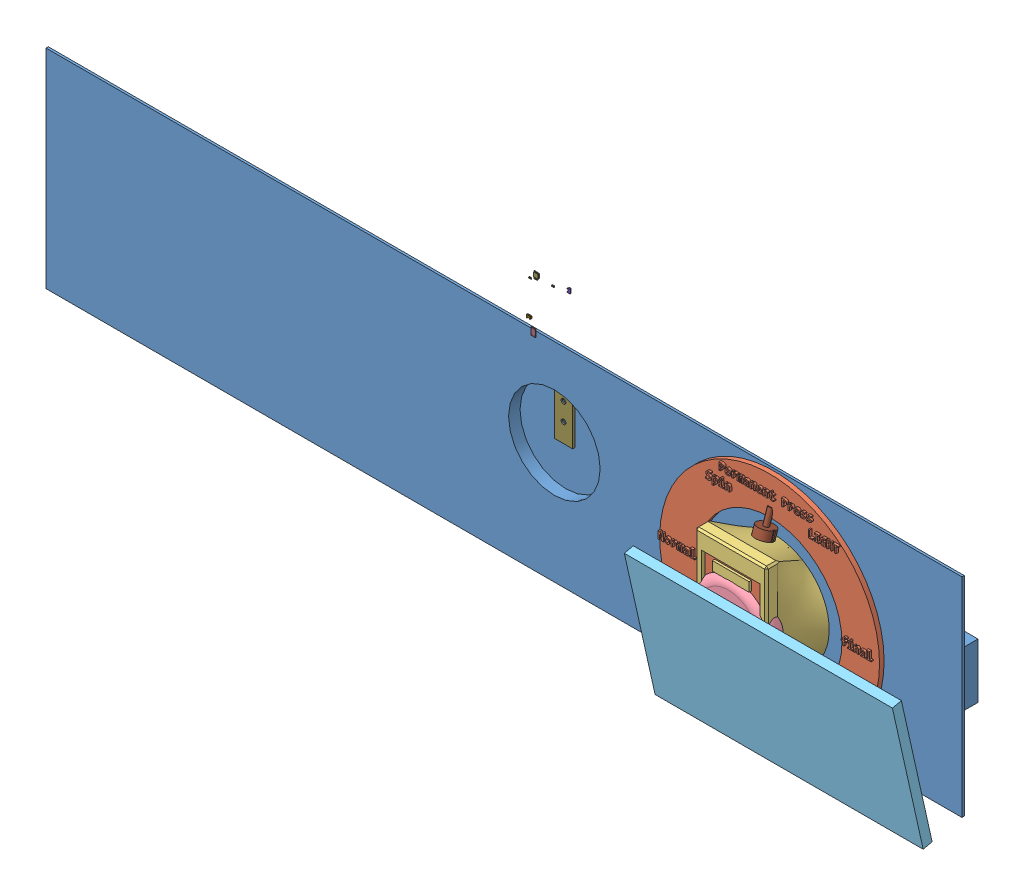
SolidWorks assembly Front Panel, configuration Default. Lengths in mm.
Overall size (635 144.46 57.15).
214 component instances, 49 part files, 26 mates.
Components (placement in the parent):
- MaytagFrontPanel-1: MaytagFrontPanel [Default] at origin size (635 144.46 26.99)
- gen4-uLCD-24PT_simplestepmodel_R_1_0-1: gen4-uLCD-24PT_simplestepmodel_R_1_0 [Default] at (28.5749 -40.2673 92.0062) x (-1 0 0) z (0 0 -1) size (171.91 172.67 8.27) (hidden)
  - gen4-uLCD-24PT_simplestepmodel_R_1_0.STEP-1: gen4-uLCD-24PT_simplestepmodel_R_1_0.STEP [Default] at origin size (171.91 172.67 8.27)
    - Assembly-24PT-NoPCB.STEP-1: Assembly-24PT-NoPCB.STEP [Default] at (-2.1876 3.7664 -0.6753) size (44.92 78.36 8.27)
      - 4DLCD-24T-QVGA-LCD.STEP-1: 4DLCD-24T-QVGA-LCD.STEP [Default] at (30.7625 31.8275 58.2815) x (0 1 0) z (0 0 -1) size (60.86 43.86 8.27)
        - 4DLCD-24T-QVGA-GLASS.STEP-1: 4DLCD-24T-QVGA-GLASS.STEP [Default] at (-0.3756 -1.6155 2.7) size (60.26 42.72 1)
        - 4DLCD-24T-QVGA-METAL.STEP-1: 4DLCD-24T-QVGA-METAL.STEP [Default] at (9.2934 0 0) size (60.26 42.72 2.7)
        - 4DLCD-24T-QVGA-LCDGLASS.STEP-1: 4DLCD-24T-QVGA-LCDGLASS.STEP [Default] at (11.9434 0 2.6) size (48.96 36.72 0.1)
        - 4DLCD-24T-QVGA-FLEX.STEP-1: 4DLCD-24T-QVGA-FLEX.STEP [Default] at (-20.8366 -9.4418 -0.1) x (0 -1 0) z (-1 0 0) size (42.86 5.67 25.87)
        - 4DLCD-24T-QVGA-BASE.STEP-1: 4DLCD-24T-QVGA-BASE.STEP [Default] at (9.2934 0 0) size (58.26 40.72 2.7)
      - gen4-24-PT.STEP-1: gen4-24-PT.STEP [Default] at (24.6025 49.8444 58.3015) size (44.83 78.36 5.75)
    - Assembly-PCB-Picaso-REV1.2.STEP-1: Assembly-PCB-Picaso-REV1.2.STEP [Default] at (11.1775 28.3756 26.4775) size (165.23 149.3 2.88)
      - Gen4-PT-REV1.2-PCBComponents.STEP-1: Gen4-PT-REV1.2-PCBComponents.STEP [Default] at (33.2756 -9.2569 32.3517) x (1 0 0) z (0 0 1) size (164.21 147.75 2.22)
        - R4.STEP-1: R4.STEP [Default] at origin size (1.6 0.8 0.46)
          - User_Library-RES_0603L.STEP-1: User_Library-RES_0603L.STEP [Default] at (129.6299 152.3699 0.0127) x (-1 0 0) z (0 1 0) size (1.6 0.46 0.8)
            - User_Library-RES_0603L_RES_0603_Lead_1.STEP-1: User_Library-RES_0603L_RES_0603_Lead_1.STEP [Default] x (-1 0 0) z (0 0 -1) size (0.25 0.45 0.8) (hidden)
            - User_Library-RES_0603L_RES_0603_Lead_1.STEP-2: User_Library-RES_0603L_RES_0603_Lead_1.STEP [Default] at origin size (0.25 0.45 0.8) (hidden)
            - User_Library-RES_0603L_RES_0603_Body_1.STEP-1: User_Library-RES_0603L_RES_0603_Body_1.STEP [Default] at origin size (1.5 0.41 0.8) (hidden)
        - R3.STEP-1: R3.STEP [Default] at origin size (0.8 1.6 0.46)
          - User_Library-RES_0603L.STEP-1: User_Library-RES_0603L.STEP [Default] at (126.2593 149.1969 0.0127) x (0 1 0) z (1 0 0) size (1.6 0.46 0.8) (hidden)
            - User_Library-RES_0603L_RES_0603_Lead_1.STEP-1: User_Library-RES_0603L_RES_0603_Lead_1.STEP [Default] x (-1 0 0) z (0 0 -1) size (0.25 0.45 0.8) (hidden)
            - User_Library-RES_0603L_RES_0603_Lead_1.STEP-2: User_Library-RES_0603L_RES_0603_Lead_1.STEP [Default] at origin size (0.25 0.45 0.8) (hidden)
            - User_Library-RES_0603L_RES_0603_Body_1.STEP-1: User_Library-RES_0603L_RES_0603_Body_1.STEP [Default] at origin size (1.5 0.41 0.8) (hidden)
        - R25.STEP-1: R25.STEP [Default] at origin size (1.6 0.8 0.46)
          - User_Library-RES_0603L.STEP-1: User_Library-RES_0603L.STEP [Default] at (129.8201 108.3301 0.0127) x (1 0 0) z (0 -1 0) size (1.6 0.46 0.8) (hidden)
            - User_Library-RES_0603L_RES_0603_Lead_1.STEP-1: User_Library-RES_0603L_RES_0603_Lead_1.STEP [Default] x (-1 0 0) z (0 0 -1) size (0.25 0.45 0.8) (hidden)
            - User_Library-RES_0603L_RES_0603_Lead_1.STEP-2: User_Library-RES_0603L_RES_0603_Lead_1.STEP [Default] at origin size (0.25 0.45 0.8) (hidden)
            - User_Library-RES_0603L_RES_0603_Body_1.STEP-1: User_Library-RES_0603L_RES_0603_Body_1.STEP [Default] at origin size (1.5 0.41 0.8) (hidden)
        - R24.STEP-1: R24.STEP [Default] at origin size (1.6 0.8 0.46)
          - User_Library-RES_0603L.STEP-1: User_Library-RES_0603L.STEP [Default] at (113.4499 109.1249 0.0127) x (-1 0 0) z (0 1 0) size (1.6 0.46 0.8) (hidden)
            - User_Library-RES_0603L_RES_0603_Lead_1.STEP-1: User_Library-RES_0603L_RES_0603_Lead_1.STEP [Default] x (-1 0 0) z (0 0 -1) size (0.25 0.45 0.8) (hidden)
            - User_Library-RES_0603L_RES_0603_Lead_1.STEP-2: User_Library-RES_0603L_RES_0603_Lead_1.STEP [Default] at origin size (0.25 0.45 0.8) (hidden)
            - User_Library-RES_0603L_RES_0603_Body_1.STEP-1: User_Library-RES_0603L_RES_0603_Body_1.STEP [Default] at origin size (1.5 0.41 0.8) (hidden)
        - R23.STEP-1: R23.STEP [Default] at origin size (0.8 1.6 0.46)
          - User_Library-RES_0603L.STEP-1: User_Library-RES_0603L.STEP [Default] at (124.125 106.8 0.0127) x (0 -1 0) z (-1 0 0) size (1.6 0.46 0.8) (hidden)
            - User_Library-RES_0603L_RES_0603_Lead_1.STEP-1: User_Library-RES_0603L_RES_0603_Lead_1.STEP [Default] x (-1 0 0) z (0 0 -1) size (0.25 0.45 0.8) (hidden)
            - User_Library-RES_0603L_RES_0603_Lead_1.STEP-2: User_Library-RES_0603L_RES_0603_Lead_1.STEP [Default] at origin size (0.25 0.45 0.8) (hidden)
            - User_Library-RES_0603L_RES_0603_Body_1.STEP-1: User_Library-RES_0603L_RES_0603_Body_1.STEP [Default] at origin size (1.5 0.41 0.8) (hidden)
        - USER_I_O.STEP-1: USER_I_O.STEP [Default] at origin size (20.5 7.15 2.05)
          - Molex-541043031-30Way-Top.STEP-1: Molex-541043031-30Way-Top.STEP [Default] at (-19.6697 44.1643 0) x (-1 0 0) z (0 1 0) size (20.5 2.05 7.15) (hidden)
        - LCD.STEP-1: LCD.STEP [Default] at origin size (25.5 7.15 2.05)
          - Molex_541044031_-_Top_-_40Way.STEP-1: Molex_541044031_-_Top_-_40Way.STEP [Default] at (-14.6243 18.1077 0) x (1 0 0) z (0 -1 0) size (25.5 2.05 7.15) (hidden)
        - U1.STEP-1: U1.STEP [Default] at origin size (3.1 4.94 1.1)
          - SW3dPS-MSOP8.STEP-1: SW3dPS-MSOP8.STEP [Default] at (125.8094 155.6968 1.1127) x (0 1 0) z (1 0 0) size (4.94 1.1 3.1) (hidden)
        - X1.STEP-1: X1.STEP [Default] at origin size (3.2 5 0.85)
          - 628705408.STEP-1: 628705408.STEP [Default] at (127.6519 120.798 0.0127) x (0 1 0) z (0 0 1) size (5 3.2 0.85) (hidden)
        - uSD1.STEP-1: uSD1.STEP [Default] at origin size (14.4 14.6 2.03)
          - 112C-TXAR-R02_C_1x.STEP-1: 112C-TXAR-R02_C_1x.STEP [Default] at (-7.7099 30.1601 0) x (-1 0 0) z (0 1 0) size (14.4 2.03 14.6) (hidden)
            - 201-1.STEP-1: 201-1.STEP [Default] at origin size (13.3 1.7 13.1) (hidden)
            - 301-1.STEP-1: 301-1.STEP [Default] at origin size (8.11 1.32 0.85) (hidden)
            - 301_1-1.STEP-1: 301_1-1.STEP [Default] at origin size (8.11 1.32 0.85) (hidden)
            - 301_2-1.STEP-1: 301_2-1.STEP [Default] at origin size (8.11 1.32 0.85) (hidden)
            - 301_3-1.STEP-1: 301_3-1.STEP [Default] at origin size (8.11 1.32 0.85) (hidden)
            - 301_4-1.STEP-1: 301_4-1.STEP [Default] at origin size (8.11 1.32 0.85) (hidden)
            - 301_5-1.STEP-1: 301_5-1.STEP [Default] at origin size (8.11 1.32 0.85) (hidden)
            - 301_6-1.STEP-1: 301_6-1.STEP [Default] at origin size (8.11 1.32 0.85) (hidden)
            - 301_7-1.STEP-1: 301_7-1.STEP [Default] at origin size (8.11 1.32 0.85) (hidden)
            - 401-1.STEP-1: 401-1.STEP [Default] at origin size (13.1 1.85 13.61) (hidden)
            - 402_L-F-1.STEP-1: 402_L-F-1.STEP [Default] at origin size (12.65 1.73 1.45) (hidden)
            - 402_R-F-1.STEP-1: 402_R-F-1.STEP [Default] at origin size (12.65 1.73 1.45) (hidden)
        - U3.STEP-1: U3.STEP [Default] at origin size (2.5 3 1.1)
          - SW3DPS-SOT-23-5-DEFAULT.STEP-1: SW3DPS-SOT-23-5-DEFAULT.STEP [Default] at (102.9447 157.8103 0.5377) x (0 -1 0) z (-1 0 0) size (3 1.1 2.5) (hidden)
        - U2.STEP-1: U2.STEP [Default] at origin size (3 2.5 1.1)
          - SW3DPS-SOT-23-5-DEFAULT.STEP-1: SW3DPS-SOT-23-5-DEFAULT.STEP [Default] at (118.6397 152.0697 0.5377) x (1 0 0) z (0 -1 0) size (3 1.1 2.5) (hidden)
        - R22.STEP-1: R22.STEP [Default] at origin size (0.8 1.6 0.46)
          - User_Library-RES_0603L.STEP-1: User_Library-RES_0603L.STEP [Default] at (124.125 109.6 0.0127) x (0 -1 0) z (-1 0 0) size (1.6 0.46 0.8) (hidden)
            - User_Library-RES_0603L_RES_0603_Lead_1.STEP-1: User_Library-RES_0603L_RES_0603_Lead_1.STEP [Default] x (-1 0 0) z (0 0 -1) size (0.25 0.45 0.8) (hidden)
            - User_Library-RES_0603L_RES_0603_Lead_1.STEP-2: User_Library-RES_0603L_RES_0603_Lead_1.STEP [Default] at origin size (0.25 0.45 0.8) (hidden)
            - User_Library-RES_0603L_RES_0603_Body_1.STEP-1: User_Library-RES_0603L_RES_0603_Body_1.STEP [Default] at origin size (1.5 0.41 0.8) (hidden)
        - R21.STEP-1: R21.STEP [Default] at origin size (1.6 0.8 0.46)
          - User_Library-RES_0603L.STEP-1: User_Library-RES_0603L.STEP [Default] at (116.3001 105.3751 0.0127) x (1 0 0) z (0 -1 0) size (1.6 0.46 0.8) (hidden)
            - User_Library-RES_0603L_RES_0603_Lead_1.STEP-1: User_Library-RES_0603L_RES_0603_Lead_1.STEP [Default] x (-1 0 0) z (0 0 -1) size (0.25 0.45 0.8) (hidden)
            - User_Library-RES_0603L_RES_0603_Lead_1.STEP-2: User_Library-RES_0603L_RES_0603_Lead_1.STEP [Default] at origin size (0.25 0.45 0.8) (hidden)
            - User_Library-RES_0603L_RES_0603_Body_1.STEP-1: User_Library-RES_0603L_RES_0603_Body_1.STEP [Default] at origin size (1.5 0.41 0.8) (hidden)
        - R20.STEP-1: R20.STEP [Default] at origin size (0.8 1.6 0.46)
          - User_Library-RES_0603L.STEP-1: User_Library-RES_0603L.STEP [Default] at (122.6251 106.7999 0.0127) x (0 -1 0) z (-1 0 0) size (1.6 0.46 0.8) (hidden)
            - User_Library-RES_0603L_RES_0603_Lead_1.STEP-1: User_Library-RES_0603L_RES_0603_Lead_1.STEP [Default] x (-1 0 0) z (0 0 -1) size (0.25 0.45 0.8) (hidden)
            - User_Library-RES_0603L_RES_0603_Lead_1.STEP-2: User_Library-RES_0603L_RES_0603_Lead_1.STEP [Default] at origin size (0.25 0.45 0.8) (hidden)
            - User_Library-RES_0603L_RES_0603_Body_1.STEP-1: User_Library-RES_0603L_RES_0603_Body_1.STEP [Default] at origin size (1.5 0.41 0.8) (hidden)
        - R19.STEP-1: R19.STEP [Default] at origin size (1.6 0.8 0.46)
          - User_Library-RES_0603L.STEP-1: User_Library-RES_0603L.STEP [Default] at (116.3001 101.2501 0.0127) x (1 0 0) z (0 -1 0) size (1.6 0.46 0.8) (hidden)
            - User_Library-RES_0603L_RES_0603_Lead_1.STEP-1: User_Library-RES_0603L_RES_0603_Lead_1.STEP [Default] x (-1 0 0) z (0 0 -1) size (0.25 0.45 0.8) (hidden)
            - User_Library-RES_0603L_RES_0603_Lead_1.STEP-2: User_Library-RES_0603L_RES_0603_Lead_1.STEP [Default] at origin size (0.25 0.45 0.8) (hidden)
            - User_Library-RES_0603L_RES_0603_Body_1.STEP-1: User_Library-RES_0603L_RES_0603_Body_1.STEP [Default] at origin size (1.5 0.41 0.8) (hidden)
        - R18.STEP-1: R18.STEP [Default] at origin size (0.8 1.6 0.46)
          - User_Library-RES_0603L.STEP-1: User_Library-RES_0603L.STEP [Default] at (109.9251 128.3999 0.0127) x (0 -1 0) z (-1 0 0) size (1.6 0.46 0.8) (hidden)
            - User_Library-RES_0603L_RES_0603_Lead_1.STEP-1: User_Library-RES_0603L_RES_0603_Lead_1.STEP [Default] x (-1 0 0) z (0 0 -1) size (0.25 0.45 0.8) (hidden)
            - User_Library-RES_0603L_RES_0603_Lead_1.STEP-2: User_Library-RES_0603L_RES_0603_Lead_1.STEP [Default] at origin size (0.25 0.45 0.8) (hidden)
            - User_Library-RES_0603L_RES_0603_Body_1.STEP-1: User_Library-RES_0603L_RES_0603_Body_1.STEP [Default] at origin size (1.5 0.41 0.8) (hidden)
        - R17.STEP-1: R17.STEP [Default] at origin size (1.6 0.8 0.46)
          - User_Library-RES_0603L.STEP-1: User_Library-RES_0603L.STEP [Default] at (116.3001 102.6251 0.0127) x (1 0 0) z (0 -1 0) size (1.6 0.46 0.8) (hidden)
            - User_Library-RES_0603L_RES_0603_Lead_1.STEP-1: User_Library-RES_0603L_RES_0603_Lead_1.STEP [Default] x (-1 0 0) z (0 0 -1) size (0.25 0.45 0.8) (hidden)
            - User_Library-RES_0603L_RES_0603_Lead_1.STEP-2: User_Library-RES_0603L_RES_0603_Lead_1.STEP [Default] at origin size (0.25 0.45 0.8) (hidden)
            - User_Library-RES_0603L_RES_0603_Body_1.STEP-1: User_Library-RES_0603L_RES_0603_Body_1.STEP [Default] at origin size (1.5 0.41 0.8) (hidden)
        - R16.STEP-1: R16.STEP [Default] at origin size (1.6 0.8 0.46)
          - User_Library-RES_0603L.STEP-1: User_Library-RES_0603L.STEP [Default] at (112.7251 101.2501 0.0127) x (1 0 0) z (0 -1 0) size (1.6 0.46 0.8) (hidden)
            - User_Library-RES_0603L_RES_0603_Lead_1.STEP-1: User_Library-RES_0603L_RES_0603_Lead_1.STEP [Default] x (-1 0 0) z (0 0 -1) size (0.25 0.45 0.8) (hidden)
            - User_Library-RES_0603L_RES_0603_Lead_1.STEP-2: User_Library-RES_0603L_RES_0603_Lead_1.STEP [Default] at origin size (0.25 0.45 0.8) (hidden)
            - User_Library-RES_0603L_RES_0603_Body_1.STEP-1: User_Library-RES_0603L_RES_0603_Body_1.STEP [Default] at origin size (1.5 0.41 0.8) (hidden)
        - R15.STEP-1: R15.STEP [Default] at origin size (1.6 0.8 0.46)
          - User_Library-RES_0603L.STEP-1: User_Library-RES_0603L.STEP [Default] at (112.7251 102.6251 0.0127) x (1 0 0) z (0 -1 0) size (1.6 0.46 0.8) (hidden)
            - User_Library-RES_0603L_RES_0603_Lead_1.STEP-1: User_Library-RES_0603L_RES_0603_Lead_1.STEP [Default] x (-1 0 0) z (0 0 -1) size (0.25 0.45 0.8) (hidden)
            - User_Library-RES_0603L_RES_0603_Lead_1.STEP-2: User_Library-RES_0603L_RES_0603_Lead_1.STEP [Default] at origin size (0.25 0.45 0.8) (hidden)
            - User_Library-RES_0603L_RES_0603_Body_1.STEP-1: User_Library-RES_0603L_RES_0603_Body_1.STEP [Default] at origin size (1.5 0.41 0.8) (hidden)
        - R14.STEP-1: R14.STEP [Default] at origin size (1.6 0.8 0.46)
          - User_Library-RES_0603L.STEP-1: User_Library-RES_0603L.STEP [Default] at (112.7251 104.0001 0.0127) x (1 0 0) z (0 -1 0) size (1.6 0.46 0.8) (hidden)
            - User_Library-RES_0603L_RES_0603_Lead_1.STEP-1: User_Library-RES_0603L_RES_0603_Lead_1.STEP [Default] x (-1 0 0) z (0 0 -1) size (0.25 0.45 0.8) (hidden)
            - User_Library-RES_0603L_RES_0603_Lead_1.STEP-2: User_Library-RES_0603L_RES_0603_Lead_1.STEP [Default] at origin size (0.25 0.45 0.8) (hidden)
            - User_Library-RES_0603L_RES_0603_Body_1.STEP-1: User_Library-RES_0603L_RES_0603_Body_1.STEP [Default] at origin size (1.5 0.41 0.8) (hidden)
        - R13.STEP-1: R13.STEP [Default] at origin size (1.6 0.8 0.46)
          - User_Library-RES_0603L.STEP-1: User_Library-RES_0603L.STEP [Default] at (112.7001 105.3751 0.0127) x (1 0 0) z (0 -1 0) size (1.6 0.46 0.8) (hidden)
            - User_Library-RES_0603L_RES_0603_Lead_1.STEP-1: User_Library-RES_0603L_RES_0603_Lead_1.STEP [Default] x (-1 0 0) z (0 0 -1) size (0.25 0.45 0.8) (hidden)
            - User_Library-RES_0603L_RES_0603_Lead_1.STEP-2: User_Library-RES_0603L_RES_0603_Lead_1.STEP [Default] at origin size (0.25 0.45 0.8) (hidden)
            - User_Library-RES_0603L_RES_0603_Body_1.STEP-1: User_Library-RES_0603L_RES_0603_Body_1.STEP [Default] at origin size (1.5 0.41 0.8) (hidden)
        - R12.STEP-1: R12.STEP [Default] at origin size (1.6 0.8 0.46)
          - User_Library-RES_0603L.STEP-1: User_Library-RES_0603L.STEP [Default] at (105.4601 129.2201 0.0127) x (1 0 0) z (0 -1 0) size (1.6 0.46 0.8) (hidden)
            - User_Library-RES_0603L_RES_0603_Lead_1.STEP-1: User_Library-RES_0603L_RES_0603_Lead_1.STEP [Default] x (-1 0 0) z (0 0 -1) size (0.25 0.45 0.8) (hidden)
            - User_Library-RES_0603L_RES_0603_Lead_1.STEP-2: User_Library-RES_0603L_RES_0603_Lead_1.STEP [Default] at origin size (0.25 0.45 0.8) (hidden)
            - User_Library-RES_0603L_RES_0603_Body_1.STEP-1: User_Library-RES_0603L_RES_0603_Body_1.STEP [Default] at origin size (1.5 0.41 0.8) (hidden)
        - R11.STEP-1: R11.STEP [Default] at origin size (0.8 1.6 0.46)
          - User_Library-RES_0603L.STEP-1: User_Library-RES_0603L.STEP [Default] at (130.8199 149.1901 0.2277) x (0 1 0) z (1 0 0) size (1.6 0.46 0.8) (hidden)
            - User_Library-RES_0603L_RES_0603_Lead_1.STEP-1: User_Library-RES_0603L_RES_0603_Lead_1.STEP [Default] x (-1 0 0) z (0 0 -1) size (0.25 0.45 0.8) (hidden)
            - User_Library-RES_0603L_RES_0603_Lead_1.STEP-2: User_Library-RES_0603L_RES_0603_Lead_1.STEP [Default] at origin size (0.25 0.45 0.8) (hidden)
            - User_Library-RES_0603L_RES_0603_Body_1.STEP-1: User_Library-RES_0603L_RES_0603_Body_1.STEP [Default] at origin size (1.5 0.41 0.8) (hidden)
        - R10.STEP-1: R10.STEP [Default] at origin size (0.8 1.6 0.46)
          - User_Library-RES_0603L.STEP-1: User_Library-RES_0603L.STEP [Default] at (105.8251 157.7749 0.0127) x (0 -1 0) z (-1 0 0) size (1.6 0.46 0.8) (hidden)
            - User_Library-RES_0603L_RES_0603_Lead_1.STEP-1: User_Library-RES_0603L_RES_0603_Lead_1.STEP [Default] x (-1 0 0) z (0 0 -1) size (0.25 0.45 0.8) (hidden)
            - User_Library-RES_0603L_RES_0603_Lead_1.STEP-2: User_Library-RES_0603L_RES_0603_Lead_1.STEP [Default] at origin size (0.25 0.45 0.8) (hidden)
            - User_Library-RES_0603L_RES_0603_Body_1.STEP-1: User_Library-RES_0603L_RES_0603_Body_1.STEP [Default] at origin size (1.5 0.41 0.8) (hidden)
        - R6.STEP-1: R6.STEP [Default] at origin size (0.8 1.6 0.46)
          - User_Library-RES_0603L.STEP-1: User_Library-RES_0603L.STEP [Default] at (111.2301 149.1199 0.0127) x (0 -1 0) z (-1 0 0) size (1.6 0.46 0.8) (hidden)
            - User_Library-RES_0603L_RES_0603_Lead_1.STEP-1: User_Library-RES_0603L_RES_0603_Lead_1.STEP [Default] x (-1 0 0) z (0 0 -1) size (0.25 0.45 0.8) (hidden)
            - User_Library-RES_0603L_RES_0603_Lead_1.STEP-2: User_Library-RES_0603L_RES_0603_Lead_1.STEP [Default] at origin size (0.25 0.45 0.8) (hidden)
            - User_Library-RES_0603L_RES_0603_Body_1.STEP-1: User_Library-RES_0603L_RES_0603_Body_1.STEP [Default] at origin size (1.5 0.41 0.8) (hidden)
        - R2.STEP-1: R2.STEP [Default] at origin size (0.8 1.6 0.46)
          - User_Library-RES_0603L.STEP-1: User_Library-RES_0603L.STEP [Default] at (123.2095 149.2217 0.0127) x (0 -1 0) z (-1 0 0) size (1.6 0.46 0.8) (hidden)
            - User_Library-RES_0603L_RES_0603_Lead_1.STEP-1: User_Library-RES_0603L_RES_0603_Lead_1.STEP [Default] x (-1 0 0) z (0 0 -1) size (0.25 0.45 0.8) (hidden)
            - User_Library-RES_0603L_RES_0603_Lead_1.STEP-2: User_Library-RES_0603L_RES_0603_Lead_1.STEP [Default] at origin size (0.25 0.45 0.8) (hidden)
            - User_Library-RES_0603L_RES_0603_Body_1.STEP-1: User_Library-RES_0603L_RES_0603_Body_1.STEP [Default] at origin size (1.5 0.41 0.8) (hidden)
        - R1.STEP-1: R1.STEP [Default] at origin size (1.6 0.8 0.46)
          - User_Library-RES_0603L.STEP-1: User_Library-RES_0603L.STEP [Default] at (129.8093 157.6717 0.0127) x (-1 0 0) z (0 1 0) size (1.6 0.46 0.8) (hidden)
            - User_Library-RES_0603L_RES_0603_Lead_1.STEP-1: User_Library-RES_0603L_RES_0603_Lead_1.STEP [Default] x (-1 0 0) z (0 0 -1) size (0.25 0.45 0.8) (hidden)
            - User_Library-RES_0603L_RES_0603_Lead_1.STEP-2: User_Library-RES_0603L_RES_0603_Lead_1.STEP [Default] at origin size (0.25 0.45 0.8) (hidden)
            - User_Library-RES_0603L_RES_0603_Body_1.STEP-1: User_Library-RES_0603L_RES_0603_Body_1.STEP [Default] at origin size (1.5 0.41 0.8) (hidden)
        - Q1.STEP-1: Q1.STEP [Default] at origin size (3 2.5 1.1)
          - SW3DPS-SOT-23-DEFAULT.STEP-1: SW3DPS-SOT-23-DEFAULT.STEP [Default] at (130.8699 128.4699 0.5127) x (-1 0 0) z (0 1 0) size (3 1.1 2.5) (hidden)
        - L1.STEP-1: L1.STEP [Default] at origin size (1.6 0.8 0.7)
          - User_Library-ECHU_PPS.STEP-1: User_Library-ECHU_PPS.STEP [Default] at (-29.8699 24.0601 0) x (1 0 0) z (0 0 1) size (1.6 0.8 0.7) (hidden)
        - D1.STEP-1: D1.STEP [Default] at origin size (3.85 1.71 1.45)
          - User_Library-SOD-123_DiodesInc.STEP-1: User_Library-SOD-123_DiodesInc.STEP [Default] at (-4.125 51.69 0.5) x (-1 0 0) z (0 0 1) size (3.85 1.7 1.45) (hidden)
        - C23.STEP-1: C23.STEP [Default] at origin size (1.6 0.8 0.6)
          - User_Library-cap_0603_lowprofile.STEP-1: User_Library-cap_0603_lowprofile.STEP [Default] at (114.1499 155.0999 0.0127) x (-1 0 0) z (0 0 1) size (1.6 0.8 0.6) (hidden)
        - C22.STEP-1: C22.STEP [Default] at origin size (0.8 1.6 0.6)
          - User_Library-cap_0603_lowprofile.STEP-1: User_Library-cap_0603_lowprofile.STEP [Default] at (111.2301 152.9099 0.0127) x (0 -1 0) z (0 0 1) size (1.6 0.8 0.6) (hidden)
        - C21.STEP-1: C21.STEP [Default] at origin size (1.6 0.8 0.6)
          - User_Library-cap_0603_lowprofile.STEP-1: User_Library-cap_0603_lowprofile.STEP [Default] at (108.1901 145.2201 0.0127) size (1.6 0.8 0.6) (hidden)
        - C20.STEP-1: C20.STEP [Default] at origin size (0.8 1.6 0.6)
          - User_Library-cap_0603_lowprofile.STEP-1: User_Library-cap_0603_lowprofile.STEP [Default] at (125.7 108.25 0.0127) x (0 -1 0) z (0 0 1) size (1.6 0.8 0.6) (hidden)
        - C19.STEP-1: C19.STEP [Default] at origin size (1.6 0.8 0.6)
          - User_Library-cap_0603_lowprofile.STEP-1: User_Library-cap_0603_lowprofile.STEP [Default] at (116.2251 109.1251 0.0127) size (1.6 0.8 0.6) (hidden)
        - C18.STEP-1: C18.STEP [Default] at origin size (0.8 1.6 0.6)
          - User_Library-cap_0603_lowprofile.STEP-1: User_Library-cap_0603_lowprofile.STEP [Default] at (119.8094 155.6219 0.0127) x (0 1 0) z (0 0 1) size (1.6 0.8 0.6) (hidden)
        - C17.STEP-1: C17.STEP [Default] at origin size (0.8 1.6 0.6)
          - User_Library-cap_0603_lowprofile.STEP-1: User_Library-cap_0603_lowprofile.STEP [Default] at (117.0499 129.4251 0.0127) x (0 1 0) z (0 0 1) size (1.6 0.8 0.6) (hidden)
        - C16.STEP-1: C16.STEP [Default] at origin size (1.6 0.8 0.6)
          - User_Library-cap_0603_lowprofile.STEP-1: User_Library-cap_0603_lowprofile.STEP [Default] at (127.7501 117.2001 0.0127) size (1.6 0.8 0.6) (hidden)
        - C15.STEP-1: C15.STEP [Default] at origin size (1.6 0.8 0.6)
          - User_Library-cap_0603_lowprofile.STEP-1: User_Library-cap_0603_lowprofile.STEP [Default] at (127.6749 124.4749 0.0127) x (-1 0 0) z (0 0 1) size (1.6 0.8 0.6) (hidden)
        - C14.STEP-1: C14.STEP [Default] at origin size (0.8 1.6 0.6)
          - User_Library-cap_0603_lowprofile.STEP-1: User_Library-cap_0603_lowprofile.STEP [Default] at (117.0499 135.1601 0.0127) x (0 1 0) z (0 0 1) size (1.6 0.8 0.6) (hidden)
        - C12.STEP-1: C12.STEP [Default] at origin size (0.8 1.6 0.6)
          - User_Library-cap_0603_lowprofile.STEP-1: User_Library-cap_0603_lowprofile.STEP [Default] at (121.2999 155.6251 0.0127) x (0 1 0) z (0 0 1) size (1.6 0.8 0.6) (hidden)
        - C11.STEP-1: C11.STEP [Default] at origin size (0.8 1.6 0.6)
          - User_Library-cap_0603_lowprofile.STEP-1: User_Library-cap_0603_lowprofile.STEP [Default] at (133.1399 122.3101 0.0127) x (0 1 0) z (0 0 1) size (1.6 0.8 0.6) (hidden)
        - C10.STEP-1: C10.STEP [Default] at origin size (0.8 1.6 0.6)
          - User_Library-cap_0603_lowprofile.STEP-1: User_Library-cap_0603_lowprofile.STEP [Default] at (117.1751 157.7999 0.0127) x (0 -1 0) z (0 0 1) size (1.6 0.8 0.6) (hidden)
        - C9.STEP-1: C9.STEP [Default] at origin size (0.8 1.6 0.6)
          - User_Library-cap_0603_lowprofile.STEP-1: User_Library-cap_0603_lowprofile.STEP [Default] at (120.0749 148.6001 0.0127) x (0 1 0) z (0 0 1) size (1.6 0.8 0.6) (hidden)
        - C8.STEP-1: C8.STEP [Default] at origin size (0.8 1.6 0.6)
          - User_Library-cap_0603_lowprofile.STEP-1: User_Library-cap_0603_lowprofile.STEP [Default] at (116.2501 152.0499 0.0127) x (0 -1 0) z (0 0 1) size (1.6 0.8 0.6) (hidden)
        - C7.STEP-1: C7.STEP [Default] at origin size (1.6 0.8 0.6)
          - User_Library-cap_0603_lowprofile.STEP-1: User_Library-cap_0603_lowprofile.STEP [Default] at (113.9801 148.5501 0.0127) size (1.6 0.8 0.6) (hidden)
        - C6.STEP-1: C6.STEP [Default] at origin size (1.6 0.8 0.6)
          - User_Library-cap_0603_lowprofile.STEP-1: User_Library-cap_0603_lowprofile.STEP [Default] at (125.3251 151.3251 0.0127) size (1.6 0.8 0.6) (hidden)
        - C5.STEP-1: C5.STEP [Default] at origin size (1.6 0.8 0.6)
          - User_Library-cap_0603_lowprofile.STEP-1: User_Library-cap_0603_lowprofile.STEP [Default] at (129.8093 156.1967 0.0127) x (-1 0 0) z (0 0 1) size (1.6 0.8 0.6) (hidden)
        - C4.STEP-1: C4.STEP [Default] at origin size (0.8 1.6 0.6)
          - User_Library-cap_0603_lowprofile.STEP-1: User_Library-cap_0603_lowprofile.STEP [Default] at (129.2845 149.1967 0.0127) x (0 -1 0) z (0 0 1) size (1.6 0.8 0.6) (hidden)
        - C3.STEP-1: C3.STEP [Default] at origin size (0.8 1.6 0.6)
          - User_Library-cap_0603_lowprofile.STEP-1: User_Library-cap_0603_lowprofile.STEP [Default] at (127.7594 149.1969 0.0127) x (0 1 0) z (0 0 1) size (1.6 0.8 0.6) (hidden)
        - C2.STEP-1: C2.STEP [Default] at origin size (0.8 1.6 0.6)
          - User_Library-cap_0603_lowprofile.STEP-1: User_Library-cap_0603_lowprofile.STEP [Default] at (124.7345 149.1967 0.0127) x (0 -1 0) z (0 0 1) size (1.6 0.8 0.6) (hidden)
        - C1.STEP-1: C1.STEP [Default] at origin size (1.6 0.8 0.6)
          - User_Library-cap_0603_lowprofile.STEP-1: User_Library-cap_0603_lowprofile.STEP [Default] at (122.3001 158.5001 0.0127) size (1.6 0.8 0.6) (hidden)
        - L4.STEP-1: L4.STEP [Default] at origin size (1.2 2 0.5)
          - 0805-Inductor.STEP-1: 0805-Inductor.STEP [Default] at (-4.7299 44.2281 0.35) x (0 1 0) z (0 0 1) size (2 1.2 0.5) (hidden)
      - Gen4-PT-REV1.2OutLine.STEP-1: Gen4-PT-REV1.2OutLine.STEP [Default] at (33.2836 -9.2486 32.3147) size (31.7 42.5 0.87)
      - RoHS2.STEP-1: RoHS2.STEP [Default] at (13.5916 10.9296 32.3507) x (0.999982 -0.005956 0) z (0 0 -1) size (3.32 3.32 0.04)
      - SD-Logo.STEP-1: SD-Logo.STEP [Default] at (18.0324 18.573 32.3507) x (0.023632 -0.999721 0) z (0 0 1) size (3.32 1.09 0.04)
      - 4D-Logo.STEP-1: 4D-Logo.STEP [Default] at (11.7637 29.6556 32.3507) size (4.06 4.06 0.05)
      - Bin.STEP-1: Bin.STEP [Default] at (8.9799 11.1717 32.3507) size (1.92 2.67 0.05)
      - CE.STEP-1: CE.STEP [Default] at (17.1637 10.7288 32.3507) size (2.89 2.06 0.05)
- LCD glass position^Front Panel-1: LCD glass position^Front Panel [Default] at (0 0 9.525) size (122.53 58.57 0) (hidden, virtual)
- LetteringPlate-1: LetteringPlate [Default] at (0 0 9.525) size (152.4 136.53 4.76) (hidden)
- LcdBezel-1: LcdBezel [plane cut lid] at origin size (76.59 84.03 38.11)
- MainKnob-1: MainKnob [Default] at (0 0 26.6594) x (0.666508 0.745498 0) z (0.745498 -0.666508 0) size (55.88 14.62 55.88) (hidden)
- Lid-1: Lid [Default] at (45.9717 -62.05 38.7041) x (1 0 0) z (0 0.975917 0.218143) size (185.85 6.35 97.82) (hidden)
- PcbMounting-1: PcbMounting [Default] at origin size (146.05 95.25 19.05)
- SparkFunQwiicQuadRelay-1: SparkFunQwiicQuadRelay [Default] at (91.44 -35.56 0) x (0 -1 0) z (1 0 0) size (82.55 17.5 50.49) (hidden)
- SparkfunQwiicSolidStateRelays-1: SparkfunQwiicSolidStateRelays [Default] at (-102.0496 1.5419 -11.1125) x (1 0 0) z (0 1 0) size (185.42 26.99 91.44) (hidden)
- ArduinoPcb-1: ArduinoPcb [Default] at (13.273 14.9776 -7.9375) x (0 -1 0) z (1 0 0) size (60.96 13.33 48.26) (hidden)
- SS-Relay-Bracket-1: SS-Relay-Bracket [Default] at (-119.2717 44.2133 7.9375) x (1 0 0) z (0 1 0) size (99.31 19.05 114.3)
- Power Switch-1: Power Switch [Default] at (-1.537 23.1581 13.8878) x (0 -0.311503 -0.950245) z (1 0 0) size (12.85 32.1 23.83) (hidden)
- SpareMountNutBracket-1: SpareMountNutBracket [Default] at (-152.4058 3.2012 0) x (-1 0 0) z (0 1 0) size (12.7 3.17 35.57)
Mates (geometry in assembly coordinates):
- Distance2: distance = 28.575 mm aligned: plane of MaytagFrontPanel-1 through (0 0 9.525) normal (0 0 1); plane of gen4-uLCD-24PT_simplestepmodel_R_1_0-1/gen4-uLCD-24PT_simplestepmodel_R_1_0.STEP-1/Assembly-24PT-NoPCB.STEP-1/4DLCD-24T-QVGA-LCD.STEP-1/4DLCD-24T-QVGA-GLASS.STEP-1 through (21.36 -25.51 38.1) normal (0 0 1)
- InPlace1: in place: plane of ? through (0 0 9.525) normal (0 0 1); plane of ? through (0 0 9.525) normal (0 0 1); moOrthogonalPlaneRef_w of ? through (0 0 9.525) normal (0 0 1); plane of ? through (0 0 9.525) normal (0 1 0); plane of ? through (0 0 9.525) normal (0 0 1); plane of ? through (0 0 9.525) normal (1 0 0); plane of ? through (0 0 9.525) normal (0 0 1); unknown of ?
- Coincident2: coincident aligned: plane of MaytagFrontPanel-1; plane of LCD glass position^Front Panel-1
- Coincident3: coincident aligned: moOrthogonalPlaneRef_w of MaytagFrontPanel-1 through (0 0 9.525) normal (0 1 0); plane of LCD glass position^Front Panel-1 through (0 0 9.525) normal (0 1 0)
- Coincident4: coincident anti-aligned: moOrthogonalPlaneRef_w of MaytagFrontPanel-1 through (0 0 9.525) normal (-1 0 0); plane of LCD glass position^Front Panel-1 through (0 0 9.525) normal (1 0 0)
- Coincident5: coincident: line of gen4-uLCD-24PT_simplestepmodel_R_1_0-1/gen4-uLCD-24PT_simplestepmodel_R_1_0.STEP-1/Assembly-24PT-NoPCB.STEP-1/4DLCD-24T-QVGA-LCD.STEP-1/4DLCD-24T-QVGA-LCDGLASS.STEP-1 through (-18.36 31.75 37.1) axis (0 -1 0)
- Coincident7: coincident: line of gen4-uLCD-24PT_simplestepmodel_R_1_0-1/gen4-uLCD-24PT_simplestepmodel_R_1_0.STEP-1/Assembly-24PT-NoPCB.STEP-1/4DLCD-24T-QVGA-LCD.STEP-1/4DLCD-24T-QVGA-LCDGLASS.STEP-1 through (18.36 31.75 37.1) axis (-1 0 0)
- InPlace2: in place: plane of ? through (0 0 9.525) normal (0 0 1); plane of ? through (0 0 9.525) normal (0 0 1); plane of ? through (0 0 9.525) normal (0 0 1); plane of ? through (0 0 9.525) normal (0 1 0); plane of ? through (0 0 9.525) normal (0 0 1); plane of ? through (0 0 9.525) normal (1 0 0); plane of ? through (0 0 9.525) normal (0 0 1); unknown of ?
- Coincident8: coincident aligned: plane of MaytagFrontPanel-1; plane of LetteringPlate-1
- Coincident9: coincident aligned: moOrthogonalPlaneRef_w of MaytagFrontPanel-1 through (0 0 9.525) normal (0 1 0); plane of LetteringPlate-1 through (0 0 9.525) normal (0 1 0)
- Coincident10: coincident anti-aligned: moOrthogonalPlaneRef_w of MaytagFrontPanel-1 through (0 0 9.525) normal (-1 0 0); plane of LetteringPlate-1 through (0 0 9.525) normal (1 0 0)
- Concentric1: concentric anti-aligned: circle of MaytagFrontPanel-1; circle of MainKnob-1
- Distance3: distance = 31.75 mm aligned: plane of MaytagFrontPanel-1 through (0 0 9.525) normal (0 0 1); plane of MainKnob-1 through (0 0 41.275) normal (0 0 1)
- Tangent2: tangent anti-aligned: torus of MainKnob-1; plane of Lid-1 through (45.9717 -60.6648 32.507) normal (0 0.218143 -0.975917)
- Parallel2: parallel anti-aligned: line of MaytagFrontPanel-1 through (-504.825 -66.675 9.525) axis (1 0 0); line of Lid-1 through (130.175 -70.944 30.2093) axis (-1 0 0)
- Coincident10: coincident aligned: plane of MaytagFrontPanel-1 through (130.175 77.7875 9.525) normal (1 0 0); plane of Lid-1 through (130.175 -70.944 30.2093) normal (1 0 0)
- Angle1: planar angle = 0.219911 rad anti-aligned: plane of MaytagFrontPanel-1 through (0 0 9.525) normal (0 0 1); plane of Lid-1 through (45.9717 -60.6648 32.507) normal (0 0.218143 -0.975917)
- Distance10: distance = 6.35 mm anti-aligned: plane of PcbMounting-1 through (0 0 6.35) normal (0 0 -1); plane of SparkFunQwiicQuadRelay-1 through (91.44 -35.56 0) normal (0 0 1)
- Coincident27: coincident aligned: plane of PcbMounting-1 through (91.44 -46.99 6.35) normal (1 0 0); plane of SparkFunQwiicQuadRelay-1 through (91.44 -35.56 -2) normal (1 0 0)
- Coincident28: coincident aligned: plane of PcbMounting-1 through (-54.61 46.99 6.35) normal (0 1 0); plane of SparkFunQwiicQuadRelay-1 through (91.44 46.99 -2) normal (0 1 0)
- Distance11: distance = 6.35 mm anti-aligned: plane of ArduinoPcb-1 through (13.273 14.9776 -7.9375) normal (0 0 1); plane of PcbMounting-1 through (0 0 -1.5875) normal (0 0 -1)
- Distance12: distance = 1.5875 mm anti-aligned: plane of ArduinoPcb-1 through (42.8625 44.45 -9.525) normal (1 0 0); plane of SparkFunQwiicQuadRelay-1 through (44.45 -35.56 -2) normal (-1 0 0)
- Distance13: distance = 2.54 mm aligned: plane of PcbMounting-1 through (-54.61 46.99 6.35) normal (0 1 0); plane of ArduinoPcb-1 through (-5.3975 44.45 -9.525) normal (0 1 0)
- Distance15: distance = 33.401 mm anti-aligned: plane of gen4-uLCD-24PT_simplestepmodel_R_1_0-1/gen4-uLCD-24PT_simplestepmodel_R_1_0.STEP-1/Assembly-24PT-NoPCB.STEP-1/4DLCD-24T-QVGA-LCD.STEP-1/4DLCD-24T-QVGA-GLASS.STEP-1 through (-21.36 -25.51 38.1) normal (-1 0 0); plane of Power Switch-1 through (12.041 41.0556 23.6373) normal (1 0 0)
- Tangent4: tangent: face of ?; plane of Power Switch-1 through (-1.537 36.433 9.5361) normal (0 0.950245 -0.311503)
- Tangent5: tangent: plane of MaytagFrontPanel-1 through (0 0 9.525) normal (0 0 1); circle of Power Switch-1
